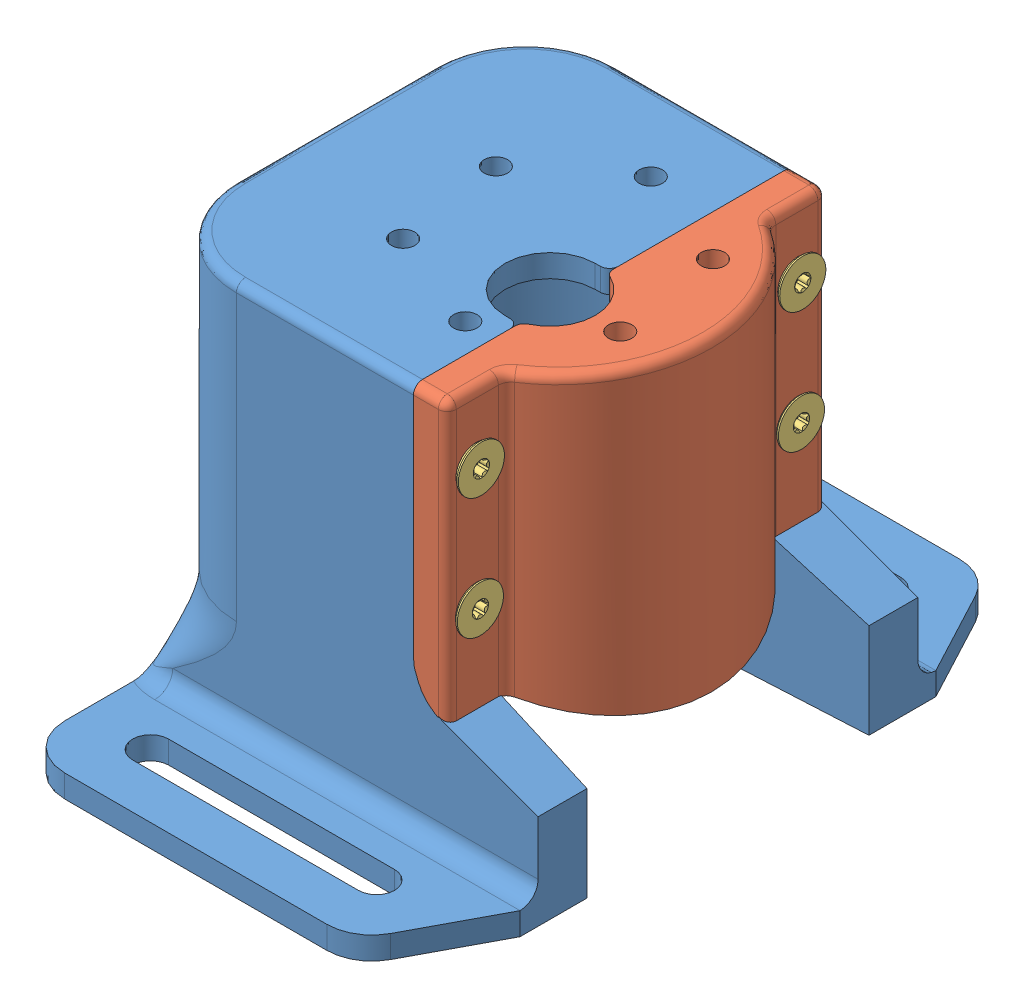
SolidWorks assembly Assem1, configuration Default. Lengths in mm.
Overall size (56.68 57.15 88.9).
6 component instances, 3 part files, 8 mates.
Components (placement in the parent):
- MotorHousingMain-1: MotorHousingMain [Default] at (-19.4474 -31.3851 11.4566) size (56.68 57.15 88.9)
- MotorHousingClamshell-1: MotorHousingClamshell [Default] at (-19.4721 25.7649 11.4566) size (15.24 43.11 53.34)
- 94414A108_ALLOY STL TORX DRIVE FLAT-HEAD SCKT CAP SCREW-1: 94414A108_ALLOY STL TORX DRIVE FLAT-HEAD SCKT CAP SCREW [94414A108] at (-1.9363 -0.8797 34.0626) x (0 -0.999686 -0.025042) z (1 0 0) size (6.48 6.48 9.78)
- 94414A108_ALLOY STL TORX DRIVE FLAT-HEAD SCKT CAP SCREW-2: 94414A108_ALLOY STL TORX DRIVE FLAT-HEAD SCKT CAP SCREW [94414A108] at (-1.796 16.2399 34.0626) x (0 -0.002044 -0.999998) z (1 0 0) size (6.48 6.48 9.78)
- 94414A108_ALLOY STL TORX DRIVE FLAT-HEAD SCKT CAP SCREW-3: 94414A108_ALLOY STL TORX DRIVE FLAT-HEAD SCKT CAP SCREW [94414A108] at (-2.0331 -0.8797 -11.1494) x (0 -0.009336 -0.999956) z (1 0 0) size (6.48 6.48 9.78)
- 94414A108_ALLOY STL TORX DRIVE FLAT-HEAD SCKT CAP SCREW-5: 94414A108_ALLOY STL TORX DRIVE FLAT-HEAD SCKT CAP SCREW [94414A108] at (-1.849 16.2399 -11.1494) x (0 -0.372746 -0.927934) z (1 0 0) size (6.48 6.48 9.78)
Mates (geometry in assembly coordinates):
- Coincident1: coincident anti-aligned: plane of MotorHousingMain-1 through (-7.2801 -31.3851 11.4566) normal (1 0 0); plane of MotorHousingClamshell-1 through (-7.2801 -18.1771 -15.2134) normal (-1 0 0)
- Coincident2: coincident: line of MotorHousingMain-1 through (-7.2801 24.4949 38.1266) axis (0 -1 0); plane of MotorHousingMain-1 through (-7.2801 -31.3851 11.4566) normal (1 0 0)
- Coincident4: coincident aligned: plane of MotorHousingMain-1 through (-19.4474 25.7649 11.4566) normal (0 1 0); plane of MotorHousingClamshell-1 through (-13.6301 25.7649 11.4566) normal (0 1 0)
- Coincident5: coincident aligned: plane of MotorHousingMain-1 through (-19.4474 22.5899 -15.2134) normal (0 0 -1); plane of MotorHousingClamshell-1 through (-7.2801 -18.1771 -15.2134) normal (0 0 -1)
- Concentric1: concentric aligned: circle of MotorHousingClamshell-1; circle of 94414A108_ALLOY STL TORX DRIVE FLAT-HEAD SCKT CAP SCREW-5
- Concentric2: concentric aligned: circle of MotorHousingClamshell-1; circle of 94414A108_ALLOY STL TORX DRIVE FLAT-HEAD SCKT CAP SCREW-3
- Concentric3: concentric aligned: circle of MotorHousingClamshell-1; circle of 94414A108_ALLOY STL TORX DRIVE FLAT-HEAD SCKT CAP SCREW-2
- Concentric4: concentric aligned: circle of MotorHousingClamshell-1; circle of 94414A108_ALLOY STL TORX DRIVE FLAT-HEAD SCKT CAP SCREW-1
